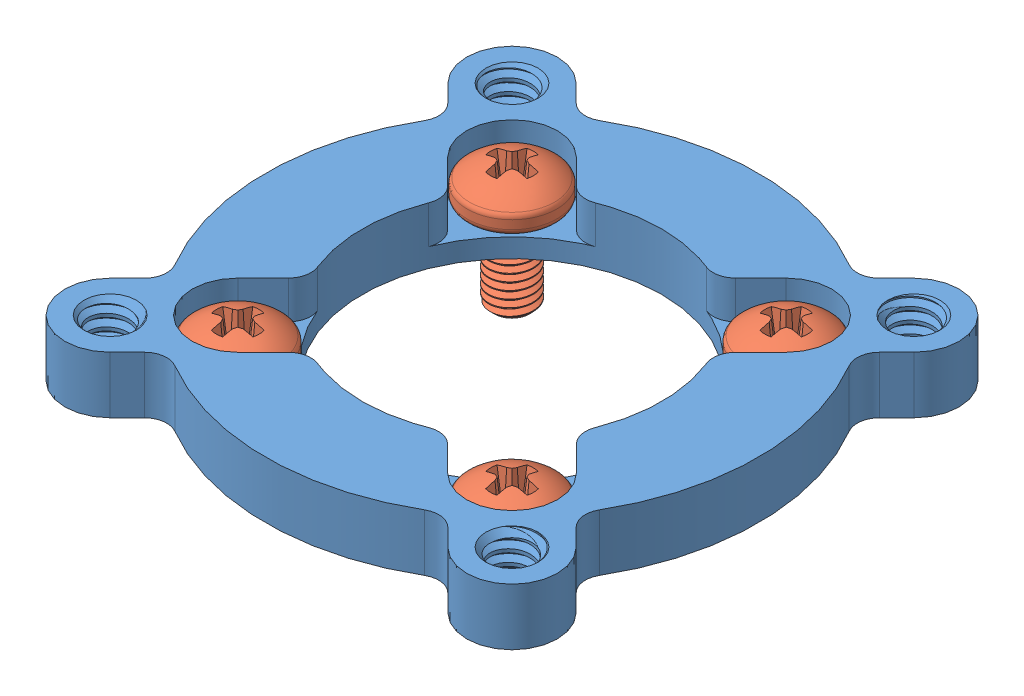
SolidWorks assembly motor mount, configuration Default. Lengths in mm.
Overall size (33.02 8.74 33.02).
5 component instances, 2 part files, 0 mates.
Components (placement in the parent):
- 555174-1: 555174 [Default] at (-58.8675 33.2863 7.1552) size (33.02 4.05 33.02)
- 555174 screw_92005A116-1: 555174 screw_92005A116 [Default] at (-68.0596 28.5563 -2.0369) x (1 0 0) z (0 1 0) size (6 6 8.48)
- 555174 screw_92005A116-2: 555174 screw_92005A116 [Default] at (-68.0596 28.5563 16.3474) x (0 0 -1) z (0 1 0) size (6 6 8.48)
- 555174 screw_92005A116-3: 555174 screw_92005A116 [Default] at (-49.6753 28.5563 16.3474) x (-1 0 0) z (0 1 0) size (6 6 8.48)
- 555174 screw_92005A116-4: 555174 screw_92005A116 [Default] at (-49.6753 28.5563 -2.0369) x (0 0 1) z (0 1 0) size (6 6 8.48)
